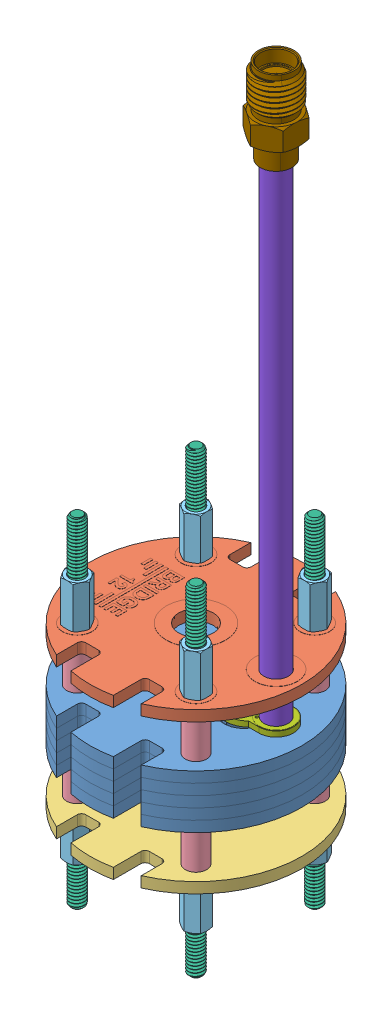
SolidWorks assembly 122001547, configuration Default. Lengths in mm.
Overall size (32.96 115.97 31.75).
31 component instances, 9 part files, 15 mates.
Components (placement in the parent):
- 121003116-1: 121003116 [Default] at origin size (31.75 1.6 31.75)
- 121003116-4: 121003116 [Default] at (0 -1.6 0) size (31.75 1.6 31.75)
- 121003116-7: 121003116 [Default] at (0 -3.2 0) size (31.75 1.6 31.75)
- 121003117-1: 121003117 [Default] at (0 11.15 0) size (31.75 1.63 31.75)
- 121003118-1: 121003118 [Default] at (0 -11.15 0) size (31.75 1.63 31.75)
- 92511A129-1: 92511A129 [92511A129] at (8.89 7.175 -8.89) x (0.864839 0 -0.502049) z (0 -1 0) size (3.17 3.17 6.35)
- 91780A023-1: 91780A023 [91780A023] at (8.89 -15.125 8.89) x (1 0 0) z (0 -1 0) size (3.17 3.67 6.66)
- 91780A023-2: 91780A023 [91780A023] at (-8.89 -15.125 8.89) x (0 0 1) z (0 -1 0) size (3.17 3.67 6.66)
- 91780A023-3: 91780A023 [91780A023] at (-8.89 -15.125 -8.89) x (-1 0 0) z (0 -1 0) size (3.17 3.67 6.66)
- 91780A023-4: 91780A023 [91780A023] at (8.89 -15.125 -8.89) x (0 0 -1) z (0 -1 0) size (3.17 3.67 6.66)
- 93225A413-1: 93225A413 [93225A413] at (8.89 0.75 8.89) x (0 -1 0) z (0 0 1) size (51.63 2.21 2.52)
- 93225A413-2: 93225A413 [93225A413] at (-8.89 0.75 8.89) x (0 -1 0) z (-1 0 0) size (51.63 2.21 2.52)
- 93225A413-3: 93225A413 [93225A413] at (-8.89 0.75 -8.89) x (0 -1 0) z (0 0 -1) size (51.63 2.21 2.52)
- 93225A413-4: 93225A413 [93225A413] at (8.89 0.75 -8.89) x (0 -1 0) z (1 0 0) size (51.63 2.21 2.52)
- 122001546-1: 122001546 [Default] at (12 5 0) x (0 0 -1) z (1 0 0) size (10.16 86.37 12.68)
  - 121003119-1: 121003119 [Default] at origin size (7.2 0.85 10.2)
  - 121003122-1: 121003122 [Default] at (0 0.8254 0) x (0.731519 0 0.681822) z (-0.681822 0 0.731519) size (3.58 77.47 3.58)
  - 901-9704-1: 901-9704 [Default] at (0 73.2154 0) x (0 1 0) z (-0.546944 0 0.837169) size (12.71 7.34 7.34)
- 121003116-10: 121003116 [Default] at (0 1.6 0) size (31.75 1.6 31.75)
- 121003116-11: 121003116 [Default] at (0 3.2 0) size (31.75 1.6 31.75)
- 92511A129-9: 92511A129 [92511A129] at (8.89 7.175 8.89) x (0.502049 0 0.864839) z (0 -1 0) size (3.17 3.17 6.35)
- 92511A129-10: 92511A129 [92511A129] at (-8.89 7.175 8.89) x (-0.864839 0 0.502049) z (0 -1 0) size (3.17 3.17 6.35)
- 92511A129-11: 92511A129 [92511A129] at (-8.89 7.175 -8.89) x (-0.502049 0 -0.864839) z (0 -1 0) size (3.17 3.17 6.35)
- 92511A129-12: 92511A129 [92511A129] at (8.89 -7.175 -8.89) x (0.864839 0 -0.502049) z (0 -1 0) size (3.17 3.17 6.35)
- 92511A129-13: 92511A129 [92511A129] at (-8.89 -7.175 -8.89) x (-0.502049 0 -0.864839) z (0 -1 0) size (3.17 3.17 6.35)
- 92511A129-14: 92511A129 [92511A129] at (8.89 -7.175 8.89) x (0.502049 0 0.864839) z (0 -1 0) size (3.17 3.17 6.35)
- 92511A129-15: 92511A129 [92511A129] at (-8.89 -7.175 8.89) x (-0.864839 0 0.502049) z (0 -1 0) size (3.17 3.17 6.35)
- 91780A023-5: 91780A023 [91780A023] at (8.89 15.125 8.89) x (1 0 0) z (0 1 0) size (3.17 3.67 6.66)
- 91780A023-6: 91780A023 [91780A023] at (-8.89 15.125 -8.89) x (-1 0 0) z (0 1 0) size (3.17 3.67 6.66)
- 91780A023-7: 91780A023 [91780A023] at (8.89 15.125 -8.89) x (0 0 1) z (0 1 0) size (3.17 3.67 6.66)
- 91780A023-8: 91780A023 [91780A023] at (-8.89 15.125 8.89) x (0 0 -1) z (0 1 0) size (3.17 3.67 6.66)
Mates (geometry in assembly coordinates):
- Concentric1: concentric aligned: cylinder of 121003116-1 through (-8.89 0.8 8.89) axis (0 1 0) radius 1.2192; cylinder of 121003117-1 through (-8.89 11.95 8.89) axis (0 1 0) radius 1.2192
- Concentric2: concentric aligned: cylinder of 121003116-1 through (8.89 0.8 8.89) axis (0 1 0) radius 1.2192; cylinder of 121003117-1 through (8.89 11.95 8.89) axis (0 1 0) radius 1.2192
- Concentric3: concentric aligned: cylinder of 121003116-7 through (-8.89 -2.4 8.89) axis (0 1 0) radius 1.2192; cylinder of 121003118-1 through (-8.89 -10.35 8.89) axis (0 1 0) radius 1.2192
- Concentric4: concentric aligned: cylinder of 121003116-7 through (8.89 -2.4 8.89) axis (0 1 0) radius 1.2192; cylinder of 121003118-1 through (8.89 -10.35 8.89) axis (0 1 0) radius 1.2192
- Concentric5: concentric aligned: cylinder of 121003116-4 through (8.89 -0.8 -8.89) axis (0 1 0) radius 1.2192; cylinder of 92511A129-1 through (8.89 4 -8.89) axis (0 1 0) radius 1.143
- Coincident1: coincident anti-aligned: plane of 121003116-11 through (0 4 0) normal (0 1 0); plane of 92511A129-1 through (8.89 4 -8.89) normal (0 -1 0)
- Coincident2: coincident anti-aligned: plane of 121003117-1 through (0 10.35 0) normal (0 -1 0); plane of 92511A129-1 through (8.89 10.35 -8.89) normal (0 1 0)
- Concentric6: concentric aligned: cylinder of 121003118-1 through (8.89 -10.35 8.89) axis (0 1 0) radius 1.2192; circle of 91780A023-1
- Coincident4: coincident anti-aligned: plane of 121003118-1 through (0 -11.95 0) normal (0 -1 0); plane of 91780A023-1 through (8.89 -11.95 10.7231) normal (0 1 0)
- Concentric7: concentric aligned: cylinder of 121003117-1 through (8.89 11.95 8.89) axis (0 1 0) radius 1.2192; circle of 93225A413-1
- Distance1: distance = 6.35 mm aligned: plane of 93225A413-1 through (8.89 -24.65 8.89) normal (0 -1 0); plane of 91780A023-1 through (8.89 -18.3 10.7231) normal (0 -1 0)
- Coincident5: coincident anti-aligned: plane of 122001546-1 through (12 5 0) normal (0 0 -1)
- Concentric8: concentric anti-aligned: cylinder of 121003117-1 through (12 10.35 0) axis (0 1 0) radius 1.8415; cylinder of 122001546-1/121003122-1 through (12 82.0254 0) axis (0 -1 0) radius 1.7907
- LimitDistance1: limit distance = 1 mm anti-aligned: plane of 122001546-1/121003119-1 through (12 5 0) normal (0 -1 0); plane of 121003116-11 through (0 4 0) normal (0 1 0)
- Coincident6: coincident anti-aligned: plane of 121003118-1 through (0 -10.35 0) normal (0 1 0); plane of 92511A129-14 through (8.89 -10.35 8.89) normal (0 -1 0)
